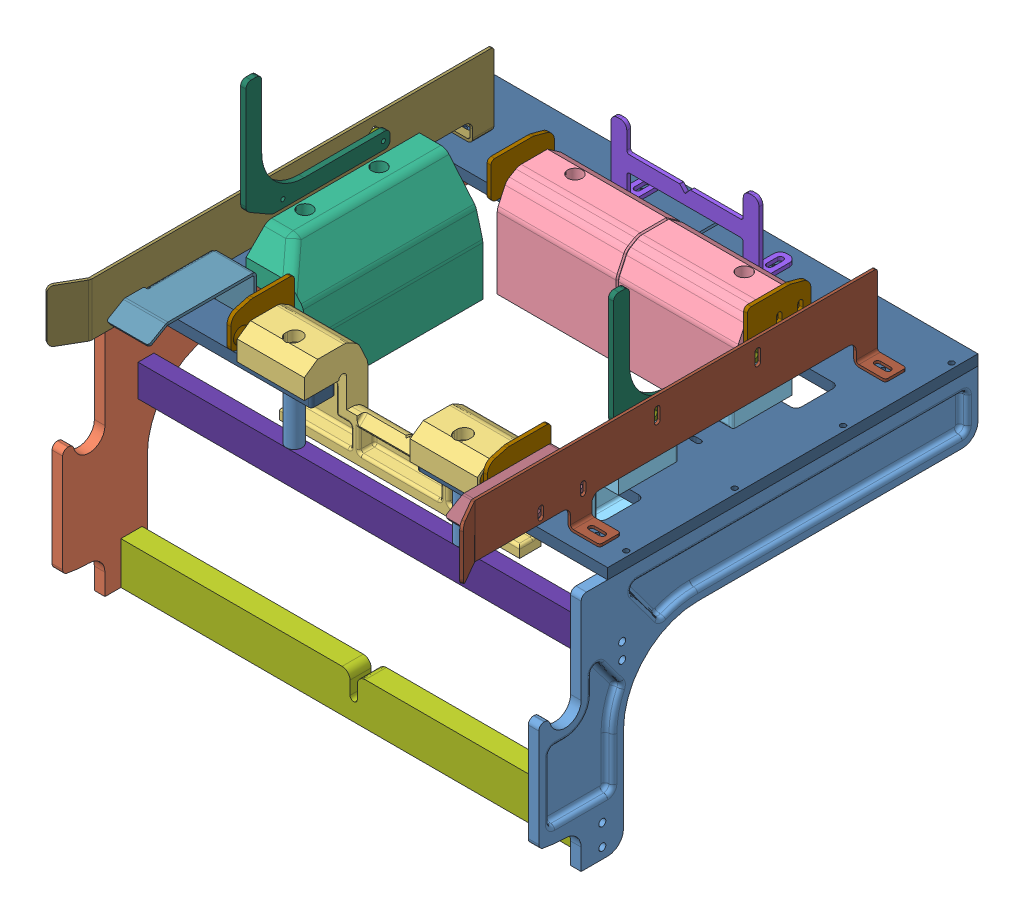
SolidWorks assembly FORMER PLATE ASSEMBLY, configuration Default. Lengths in mm.
Overall size (584.2 511.18 624.29).
42 component instances, 23 part files, 112 mates.
Components (placement in the parent):
- R&D5959 SHOW CARTON 5-30-18 LG-1: R&D5959 SHOW CARTON 5-30-18 LG [DEFAULT] at (0 -512.7625 36.5125) x (-1 0 0) z (0 0 -1) size (457.2 400.72 715.96) (hidden)
- MOUNT RIGHT-1: MOUNT RIGHT [Default] at (285.75 -156.3688 41.275) size (12.7 287.34 527.05)
- MOUNT LEFT-3: MOUNT LEFT [Default] at (-285.75 -156.3688 41.275) size (12.7 287.34 527.05)
- FOLDING PLATE BOTTOM-2: FOLDING PLATE BOTTOM [Default] at (0 -25.4 192.5637) size (288.13 120.65 76.2)
- FOLDING PLATE TOP-2: FOLDING PLATE TOP [Default] at (0 -25.4 -119.5387) x (-1 0 0) z (0 0 -1) size (288.13 120.65 76.2)
- FOLDING PLATE RIGHT-1: FOLDING PLATE RIGHT [Default] at (185.42 -18.2563 36.5125) x (0 0 -1) z (1 0 0) size (207.96 134.94 76.2)
- FOLDING PLATE LEFT-1: FOLDING PLATE LEFT [Default] at (-185.42 -18.2563 36.5125) x (0 0 1) z (-1 0 0) size (207.96 134.94 76.2)
- SPREADER BOTTOM-1: SPREADER BOTTOM [Default] at (0 -274.6375 222.25) x (1 0 0) z (0 0 -1) size (558.8 50.8 25.4)
- STOP RAIL-1: STOP RAIL [Default] at (0 0 -162.7188) x (0 0 -1) z (1 0 0) size (44.45 88.9 177.8)
- MINOR PLATE-1: MINOR PLATE [Default] at (156.2398 26.9875 192.5637) x (0 0 1) z (-1 0 0) size (76.2 44.45 4.55)
- MINOR PLATE-2: MINOR PLATE [Default] at (151.6856 26.9875 -119.5387) x (0 0 -1) z (1 0 0) size (76.2 44.45 4.55)
- MINOR PLATE-3: MINOR PLATE [Default] at (-156.2398 26.9875 -119.5387) x (0 0 -1) z (1 0 0) size (76.2 44.45 4.55)
- MINOR PLATE-4: MINOR PLATE [Default] at (-151.6856 26.9875 192.5637) x (0 0 1) z (-1 0 0) size (76.2 44.45 4.55)
- MAIN PLATE-2: MAIN PLATE [Default] at (0 -6.35 0) x (0 1 0) z (1 0 0) size (15.37 537.85 584.2)
- GUIDE RAIL-1: GUIDE RAIL [Default] at (228.6 0 79.375) x (-1 0 0) z (0 0 -1) size (38.1 88.9 517.3)
- GUIDE RAIL MIRROR-1: GUIDE RAIL MIRROR [Default] at (-228.6 0 79.375) x (-1 0 0) z (0 0 -1) size (38.1 88.9 517.3)
- SIDE GUIDE RIGHT-1: SIDE GUIDE RIGHT [Default] at (228.6 49.2125 216.6937) x (-1 0 0) z (0 0 1) size (50.8 76.2 129.64)
- SIDE GUIDE LEFT-1: SIDE GUIDE LEFT [Default] at (-228.6 49.2125 216.6937) x (-1 0 0) z (0 0 1) size (50.8 76.2 129.64)
- TOP GUIDE-1: TOP GUIDE [Default] at (223.8375 68.2625 57.9438) x (0 0 1) z (-1 0 0) size (173.02 152.4 6.35)
- TOP GUIDE-2: TOP GUIDE [Default] at (-217.4875 68.2625 57.9438) x (0 0 1) z (-1 0 0) size (173.02 152.4 6.35)
- SPACER2-1: SPACER2 [Default] at (226.2188 68.2625 -18.2563) x (0 0 -1) z (-1 0 0) size (15.88 15.88 4.76)
- SPACER2-3: SPACER2 [Default] at (226.2188 68.2625 102.3938) x (0 0 -1) z (-1 0 0) size (15.88 15.88 4.76)
- SPACER2-4: SPACER2 [Default] at (-226.2188 68.2625 -18.2563) x (0 0.924225 0.381849) z (1 0 0) size (15.88 15.88 4.76)
- SPACER2-5: SPACER2 [Default] at (-226.2188 68.2625 102.3938) x (0 0.99513 -0.098573) z (1 0 0) size (15.88 15.88 4.76)
- SPREADER TOP-1: SPREADER TOP [Default] at (0 -95.25 204.7875) x (-1 0 0) z (0 0 -1) size (558.8 38.1 19.05)
- SPACER1-1: SPACER1 [Default] at (147.8756 17.4625 -119.5387) x (0 0 -1) z (1 0 0) size (19.05 19.05 7.62)
- SPACER1-2: SPACER1 [Default] at (147.8756 17.4625 -144.9387) x (0 -0.924225 -0.381849) z (-1 0 0) size (19.05 19.05 7.62)
- SPACER1-3: SPACER1 [Default] at (147.8756 17.4625 192.5637) x (0 -0.924225 -0.381849) z (-1 0 0) size (19.05 19.05 7.62)
- SPACER1-4: SPACER1 [Default] at (147.8756 17.4625 217.9638) x (0 -0.924225 -0.381849) z (-1 0 0) size (19.05 19.05 7.62)
- SPACER1-5: SPACER1 [Default] at (-147.8756 17.4625 192.5637) x (0 0 -1) z (1 0 0) size (19.05 19.05 7.62)
- SPACER1-6: SPACER1 [Default] at (-147.8756 17.4625 217.9638) x (0 0 -1) z (1 0 0) size (19.05 19.05 7.62)
- SPACER1-7: SPACER1 [Default] at (-147.8756 17.4625 -119.5387) x (0 0 -1) z (1 0 0) size (19.05 19.05 7.62)
- SPACER1-8: SPACER1 [Default] at (-147.8756 17.4625 -144.9387) x (0 0 -1) z (1 0 0) size (19.05 19.05 7.62)
- BOLT MOUNT-1: BOLT MOUNT [Default] at (-101.6 -44.45 204.7875) x (1 0 0) z (0 -1 0) size (19.05 19.05 63.5)
- BOLT MOUNT-2: BOLT MOUNT [Default] at (101.6 -44.45 204.7875) x (0.877142 0 -0.48023) z (0 1 0) size (19.05 19.05 63.5)
- NUTPLATE LEFT AND RIGHT-1: NUTPLATE LEFT AND RIGHT [Default] at (212.4075 -15.875 36.5125) x (0 1 0) z (0 0 1) size (6.35 19.05 114.3)
- NUTPLATE LEFT AND RIGHT-2: NUTPLATE LEFT AND RIGHT [Default] at (-212.4075 -15.875 36.5125) x (0 -1 0) z (0 0 1) size (6.35 19.05 114.3)
- NUTPLATE TOP-1: NUTPLATE TOP [Default] at (0 -15.875 -132.2387) x (0 1 0) z (-1 0 0) size (6.35 19.05 228.6)
- NUTPLATE1-1: NUTPLATE1 [Default] at (123.4916 12.7 205.2637) x (0 0 -1) z (1 0 0) size (41.27 25.4 4.76)
- NUTPLATE1-2: NUTPLATE1 [Default] at (-128.2541 12.7 205.2637) x (0 0 -1) z (1 0 0) size (41.27 25.4 4.76)
- NUTPLATE1-3: NUTPLATE1 [Default] at (-128.3176 12.7 -132.2387) x (0 0 -1) z (1 0 0) size (41.27 25.4 4.76)
- NUTPLATE1-4: NUTPLATE1 [Default] at (128.3176 12.7 -132.2387) x (0 0 1) z (-1 0 0) size (41.27 25.4 4.76)
Mates (geometry in assembly coordinates):
- Coincident171: coincident: plane of MOUNT RIGHT-1 through (279.4 -12.7 304.8) normal (0 1 0); plane of MAIN PLATE-2 through (736.7814 -12.7 222.25) normal (0 -1 0)
- Coincident172: coincident: plane of MAIN PLATE-2 through (0 -6.35 0) normal (1 0 0); plane of assembly through (0 0 0) normal (1 0 0)
- Coincident173: coincident: plane of MAIN PLATE-2 through (0 -6.35 0) normal (0 0 1); plane of assembly through (0 0 0) normal (0 0 1)
- Coincident174: coincident: plane of MAIN PLATE-2 through (736.7814 0 222.25) normal (0 1 0); plane of assembly through (0 0 0) normal (0 1 0)
- Coincident175: coincident: plane of MAIN PLATE-2 through (736.7814 0 222.25) normal (0 1 0); plane of FOLDING PLATE BOTTOM-2 through (-144.0666 0 230.6637) normal (0 -1 0)
- Coincident176: coincident: plane of FOLDING PLATE TOP-2 through (0 -25.4 -119.5387) normal (-1 0 0); plane of assembly through (0 0 0) normal (1 0 0)
- Coincident177: coincident: plane of MAIN PLATE-2 through (736.7814 0 222.25) normal (0 1 0); plane of FOLDING PLATE TOP-2 through (144.0666 0 -157.6387) normal (0 -1 0)
- Coincident179: coincident: plane of R&D5959 SHOW CARTON 5-30-18 LG-1 through (0 -512.7625 36.5125) normal (-1 0 0); plane of assembly through (0 0 0) normal (1 0 0)
- Coincident182: coincident: plane of MAIN PLATE-2 through (736.7814 0 222.25) normal (0 1 0); plane of FOLDING PLATE RIGHT-1 through (223.52 0 140.4948) normal (0 -1 0)
- Coincident186: coincident: plane of FOLDING PLATE RIGHT-1 through (223.52 49.2125 140.4938) normal (0 1 0); plane of FOLDING PLATE LEFT-1 through (-223.52 49.2125 -67.4688) normal (0 1 0)
- Coincident191: coincident: plane of STOP RAIL-1 through (0 0 -162.7188) normal (1 0 0); plane of assembly through (0 0 0) normal (1 0 0)
- Coincident192: coincident: plane of MAIN PLATE-2 through (736.7814 0 222.25) normal (0 1 0); plane of STOP RAIL-1 through (88.9 0 -162.7188) normal (0 -1 0)
- Coincident196: coincident: plane of SPREADER BOTTOM-1 through (0 -274.6375 222.25) normal (1 0 0); plane of assembly through (0 0 0) normal (1 0 0)
- Coincident197: coincident: plane of FOLDING PLATE TOP-2 through (144.0656 34.925 -157.6387) normal (1 0 0); plane of SPACER1-1 through (144.0656 17.4625 -119.5387) normal (-1 0 0)
- Coincident1981: coincident: plane of FOLDING PLATE TOP-2 through (144.0656 34.925 -157.6387) normal (1 0 0); plane of SPACER1-2 through (144.0656 17.4625 -144.9387) normal (-1 0 0)
- Concentric591: concentric: cylinder of FOLDING PLATE BOTTOM-2 through (144.0656 17.4625 192.5637) axis (1 0 0) radius 3.2; cylinder of SPACER1-3 through (151.6866 17.4625 192.5637) axis (-1 0 0) radius 3.3782
- Coincident1991: coincident: plane of FOLDING PLATE BOTTOM-2 through (144.0656 34.925 230.6637) normal (1 0 0); plane of SPACER1-3 through (144.0656 17.4625 192.5637) normal (-1 0 0)
- Concentric601: concentric: cylinder of FOLDING PLATE BOTTOM-2 through (144.0656 17.4625 217.9638) axis (1 0 0) radius 3.2; cylinder of SPACER1-4 through (151.6866 17.4625 217.9638) axis (-1 0 0) radius 3.3782
- Coincident2001: coincident: plane of FOLDING PLATE BOTTOM-2 through (144.0656 34.925 230.6637) normal (1 0 0); plane of SPACER1-4 through (144.0656 17.4625 217.9638) normal (-1 0 0)
- Concentric611: concentric: cylinder of FOLDING PLATE BOTTOM-2 through (-144.0656 17.4625 192.5637) axis (-1 0 0) radius 3.2; cylinder of SPACER1-5 through (-151.6866 17.4625 192.5637) axis (1 0 0) radius 3.3782
- Coincident2011: coincident: plane of FOLDING PLATE BOTTOM-2 through (-144.0656 34.925 230.6637) normal (-1 0 0); plane of SPACER1-5 through (-144.0656 17.4625 192.5637) normal (1 0 0)
- Concentric621: concentric: cylinder of FOLDING PLATE BOTTOM-2 through (-144.0656 17.4625 217.9638) axis (-1 0 0) radius 3.2; cylinder of SPACER1-6 through (-151.6866 17.4625 217.9638) axis (1 0 0) radius 3.3782
- Coincident2021: coincident: plane of FOLDING PLATE BOTTOM-2 through (-144.0656 34.925 230.6637) normal (-1 0 0); plane of SPACER1-6 through (-144.0656 17.4625 217.9638) normal (1 0 0)
- Concentric631: concentric: cylinder of FOLDING PLATE TOP-2 through (-144.0656 17.4625 -119.5387) axis (-1 0 0) radius 3.2; cylinder of SPACER1-7 through (-151.6866 17.4625 -119.5387) axis (1 0 0) radius 3.3782
- Coincident2031: coincident: plane of FOLDING PLATE TOP-2 through (-144.0656 34.925 -157.6387) normal (-1 0 0); plane of SPACER1-7 through (-144.0656 17.4625 -119.5387) normal (1 0 0)
- Concentric641: concentric: cylinder of FOLDING PLATE TOP-2 through (-144.0656 17.4625 -144.9387) axis (-1 0 0) radius 3.2; cylinder of SPACER1-8 through (-151.6866 17.4625 -144.9387) axis (1 0 0) radius 3.3782
- Coincident2041: coincident: plane of FOLDING PLATE TOP-2 through (-144.0656 34.925 -157.6387) normal (-1 0 0); plane of SPACER1-8 through (-144.0656 17.4625 -144.9387) normal (1 0 0)
- Coincident205: coincident: plane of MINOR PLATE-1 through (151.6856 4.7625 154.4638) normal (-1 0 0); plane of SPACER1-4 through (151.6856 17.4625 217.9638) normal (1 0 0)
- Concentric65: concentric: cylinder of MINOR PLATE-1 through (156.2398 17.4625 217.9638) axis (-1 0 0) radius 3.175; cylinder of SPACER1-4 through (151.6866 17.4625 217.9638) axis (-1 0 0) radius 3.3782
- Concentric66: concentric: cylinder of MINOR PLATE-1 through (156.2398 17.4625 192.5637) axis (-1 0 0) radius 3.175; circle of SPACER1-3
- Coincident206: coincident: plane of SPACER1-1 through (151.6856 17.4625 -119.5387) normal (1 0 0); plane of MINOR PLATE-2 through (151.6856 4.7625 -81.4387) normal (-1 0 0)
- Concentric67: concentric: circle of SPACER1-1; cylinder of MINOR PLATE-2 through (151.6856 17.4625 -119.5387) axis (1 0 0) radius 3.175
- Concentric68: concentric: cylinder of SPACER1-2 through (151.6866 17.4625 -144.9387) axis (-1 0 0) radius 3.3782; cylinder of MINOR PLATE-2 through (151.6856 17.4625 -144.9387) axis (1 0 0) radius 3.175
- Coincident207: coincident: plane of SPACER1-7 through (-151.6856 17.4625 -119.5387) normal (-1 0 0); plane of MINOR PLATE-3 through (-151.6856 4.7625 -81.4387) normal (1 0 0)
- Concentric69: concentric: cylinder of SPACER1-7 through (-151.6866 17.4625 -119.5387) axis (1 0 0) radius 3.3782; cylinder of MINOR PLATE-3 through (-156.2398 17.4625 -119.5387) axis (1 0 0) radius 3.175
- Concentric70: concentric: cylinder of SPACER1-8 through (-144.0656 17.4625 -144.9387) axis (-1 0 0) radius 9.525; cylinder of MINOR PLATE-3 through (-156.2398 17.4625 -144.9387) axis (1 0 0) radius 3.175
- Coincident208: coincident: plane of SPACER1-6 through (-151.6856 17.4625 217.9638) normal (-1 0 0); plane of MINOR PLATE-4 through (-151.6856 4.7625 154.4638) normal (1 0 0)
- Concentric71: concentric: circle of SPACER1-5; cylinder of MINOR PLATE-4 through (-151.6856 17.4625 192.5637) axis (-1 0 0) radius 3.175
- Concentric72: concentric: cylinder of SPACER1-6 through (-151.6866 17.4625 217.9638) axis (1 0 0) radius 3.3782; cylinder of MINOR PLATE-4 through (-151.6856 17.4625 217.9638) axis (-1 0 0) radius 3.175
- Coincident2047: coincident: plane of MOUNT RIGHT-1 through (292.1 -300.0375 -222.25) normal (0 0 -1); plane of MAIN PLATE-2 through (736.7814 -12.7 -222.25) normal (0 0 -1)
- Coincident2048: coincident: plane of MOUNT RIGHT-1 through (292.1 -12.7 304.8) normal (1 0 0); plane of MAIN PLATE-2 through (292.1 -6.35 0) normal (1 0 0)
- Coincident2049: coincident: plane of MAIN PLATE-2 through (736.7814 -12.7 222.25) normal (0 -1 0); plane of MOUNT LEFT-3 through (-292.1 -12.7 304.8) normal (0 1 0)
- Coincident2050: coincident: plane of MAIN PLATE-2 through (736.7814 -12.7 -222.25) normal (0 0 -1); plane of MOUNT LEFT-3 through (-279.4 -300.0375 -222.25) normal (0 0 -1)
- Coincident2051: coincident: plane of MAIN PLATE-2 through (-292.1 -6.35 55.6563) normal (-1 0 0); plane of MOUNT LEFT-3 through (-292.1 -12.7 304.8) normal (-1 0 0)
- Distance13: distance = 19.05 mm: plane of SPREADER BOTTOM-1 through (279.4 -249.2375 234.95) normal (0 0 1); plane of MOUNT LEFT-3 through (-292.101 -12.7 254) normal (0 0 1)
- Coincident2053: coincident: plane of SPREADER BOTTOM-1 through (-279.4 -300.0375 209.55) normal (0 -1 0); plane of MOUNT LEFT-3 through (-292.1 -300.0375 304.8) normal (0 -1 0)
- Coincident2055: coincident: plane of MAIN PLATE-2 through (736.7814 0 222.25) normal (0 1 0); plane of GUIDE RAIL-1 through (228.6 0 -161.925) normal (0 -1 0)
- Coincident2056: coincident: plane of GUIDE RAIL-1 through (228.6 88.9 -161.925) normal (-1 0 0); plane of SIDE GUIDE RIGHT-1 through (228.6 30.1625 254.7937) normal (1 0 0)
- Coincident2059: coincident: plane of FOLDING PLATE RIGHT-1 through (223.52 49.2125 140.4938) normal (0 1 0); plane of SIDE GUIDE RIGHT-1 through (228.6 49.2125 254.7937) normal (0 1 0)
- Coincident2060: coincident: plane of MAIN PLATE-2 through (241.3 -12.701 178.5938) normal (0 0 -1); plane of SIDE GUIDE RIGHT-1 through (223.8375 44.45 178.5938) normal (0 0 -1)
- Coincident2062: coincident: plane of MAIN PLATE-2 through (736.7814 0 222.25) normal (0 1 0); plane of GUIDE RAIL MIRROR-1 through (-228.6 0 -161.925) normal (0 -1 0)
- Coincident2063: coincident: plane of GUIDE RAIL-1 through (234.95 6.35 -161.925) normal (0 0 -1); plane of GUIDE RAIL MIRROR-1 through (-234.95 6.35 -161.925) normal (0 0 -1)
- Coincident2065: coincident: plane of SIDE GUIDE RIGHT-1 through (228.6 46.0375 254.7937) normal (0 -1 0); plane of SIDE GUIDE LEFT-1 through (-228.6 46.0375 254.7937) normal (0 -1 0)
- Coincident2066: coincident: plane of GUIDE RAIL MIRROR-1 through (-228.6 88.9 -161.925) normal (1 0 0); plane of SIDE GUIDE LEFT-1 through (-228.6 30.1625 254.7937) normal (-1 0 0)
- Coincident2067: coincident: plane of SIDE GUIDE RIGHT-1 through (228.6 49.2125 173.8312) normal (0 0 -1); plane of SIDE GUIDE LEFT-1 through (-228.6 49.2125 173.8312) normal (0 0 -1)
- Parallel1: parallel: plane of MAIN PLATE-2 through (736.7814 0 222.25) normal (0 1 0); plane of STOP RAIL-1 through (88.9 4.5542 -162.7188) normal (0 1 0)
- Distance4: distance = 1.27 mm: plane of FOLDING PLATE TOP-2 through (-144.0656 -85.725 -81.4387) normal (0 0 1); line of MAIN PLATE-2 through (-146.05 -512.3053 -80.1688) axis (1 0 0)
- Distance5: distance = 1.27 mm: line of MAIN PLATE-2 through (-146.05 -512.3053 153.1937) axis (1 0 0); plane of FOLDING PLATE BOTTOM-2 through (144.0656 -85.725 154.4638) normal (0 0 -1)
- Distance6: distance = 1.27 mm: plane of FOLDING PLATE LEFT-1 through (-147.32 -85.725 140.4938) normal (1 0 0); line of MAIN PLATE-2 through (-146.05 -512.3053 -80.1688) axis (0 0 1)
- Distance7: distance = 1.27 mm: plane of FOLDING PLATE RIGHT-1 through (147.32 -85.725 -67.4688) normal (-1 0 0); line of MAIN PLATE-2 through (146.05 -512.3053 -80.1688) axis (0 0 1)
- Coincident2077: coincident: line of MAIN PLATE-2 through (146.05 -512.3053 36.5125) axis (-1 0 0); plane of FOLDING PLATE LEFT-1 through (-185.42 -18.2563 36.5125) normal (0 0 1)
- Coincident2078: coincident: plane of FOLDING PLATE BOTTOM-2 through (0 -25.4 192.5637) normal (1 0 0); plane of assembly through (0 0 0) normal (1 0 0)
- Coincident2081: coincident: line of MAIN PLATE-2 through (146.05 -512.3053 36.5125) axis (-1 0 0); plane of FOLDING PLATE RIGHT-1 through (185.42 -18.2563 36.5125) normal (0 0 -1)
- Distance8: distance = 15.875 mm: plane of MAIN PLATE-2 through (736.7814 -12.7 222.25) normal (0 0 1); plane of GUIDE RAIL-1 through (266.7 25.4 206.375) normal (0 0 1)
- Coincident2091: coincident: plane of TOP GUIDE-1 through (223.8375 58.7375 -30.9563) normal (1 0 0); plane of SPACER2-1 through (223.8375 68.2625 -18.2563) normal (-1 0 0)
- Concentric642: concentric: cylinder of TOP GUIDE-1 through (217.4875 68.2625 -18.2563) axis (-1 0 0) radius 2.5; cylinder of SPACER2-1 through (223.8375 68.2625 -18.2563) axis (1 0 0) radius 7.9375
- Concentric6431: concentric: cylinder of TOP GUIDE-1 through (217.4875 68.2625 102.3938) axis (-1 0 0) radius 2.5; cylinder of SPACER2-3 through (228.601 68.2625 102.3938) axis (-1 0 0) radius 3.3782
- Coincident20921: coincident: plane of TOP GUIDE-1 through (223.8375 58.7375 -30.9563) normal (1 0 0); plane of SPACER2-3 through (223.8375 68.2625 102.3938) normal (-1 0 0)
- Coincident2093: coincident: plane of GUIDE RAIL-1 through (228.6 88.9 -161.925) normal (-1 0 0); plane of SPACER2-1 through (228.6 68.2625 -18.2563) normal (1 0 0)
- Distance11: distance = 6.35 mm: plane of FOLDING PLATE RIGHT-1 through (223.52 49.2125 140.4938) normal (0 0 1); plane of TOP GUIDE-1 through (217.4875 77.7875 146.8438) normal (0 0 1)
- Distance9: distance = 9.525 mm: plane of FOLDING PLATE RIGHT-1 through (223.52 49.2125 140.4938) normal (0 1 0); plane of TOP GUIDE-1 through (217.4875 58.7375 -30.9563) normal (0 -1 0)
- Coincident2097: coincident: plane of TOP GUIDE-2 through (-223.8375 58.7375 -30.9563) normal (-1 0 0); plane of SPACER2-4 through (-223.8375 68.2625 -18.2563) normal (1 0 0)
- Concentric644: concentric: cylinder of TOP GUIDE-2 through (-223.8375 68.2625 -18.2563) axis (-1 0 0) radius 2.5; cylinder of SPACER2-4 through (-228.601 68.2625 -18.2563) axis (1 0 0) radius 3.3782
- Concentric6451: concentric: cylinder of TOP GUIDE-2 through (-223.8375 68.2625 102.3938) axis (-1 0 0) radius 2.5; cylinder of SPACER2-5 through (-228.601 68.2625 102.3938) axis (1 0 0) radius 3.3782
- Coincident20981: coincident: plane of TOP GUIDE-2 through (-223.8375 58.7375 -30.9563) normal (-1 0 0); plane of SPACER2-5 through (-223.8375 68.2625 102.3938) normal (1 0 0)
- Coincident2099: coincident: plane of GUIDE RAIL MIRROR-1 through (-228.6 88.9 -161.925) normal (1 0 0); plane of SPACER2-5 through (-228.6 68.2625 102.3938) normal (-1 0 0)
- Distance12: distance = 6.35 mm: plane of FOLDING PLATE LEFT-1 through (-223.52 49.2125 140.4938) normal (0 0 1); plane of TOP GUIDE-2 through (-223.8375 77.7875 146.8438) normal (0 0 1)
- Distance10: distance = 9.525 mm: plane of FOLDING PLATE LEFT-1 through (-223.52 49.2125 -67.4688) normal (0 1 0); plane of TOP GUIDE-2 through (-223.8375 58.7375 -30.9563) normal (0 -1 0)
- Coincident2102: coincident: plane of MAIN PLATE-2 through (736.7814 -12.7 222.25) normal (0 -1 0); plane of NUTPLATE TOP-1 through (-114.3 -12.7 -141.7637) normal (0 1 0)
- Coincident2103: coincident: plane of NUTPLATE TOP-1 through (0 -15.875 -132.2387) normal (-1 0 0); plane of assembly through (0 0 0) normal (1 0 0)
- Concentric646: concentric: cylinder of FOLDING PLATE TOP-2 through (101.6 34.925 -132.2387) axis (0 1 0) radius 3.3; cylinder of NUTPLATE TOP-1 through (101.6 -12.7 -132.2387) axis (0 1 0) radius 2.5
- Coincident2104: coincident: plane of MAIN PLATE-2 through (736.7814 -12.7 222.25) normal (0 -1 0); plane of NUTPLATE LEFT AND RIGHT-1 through (202.8825 -12.7 93.6625) normal (0 1 0)
- Coincident2105: coincident: plane of MAIN PLATE-2 through (736.7814 -12.7 222.25) normal (0 -1 0); plane of NUTPLATE LEFT AND RIGHT-2 through (-202.8825 -12.7 93.6625) normal (0 1 0)
- Coincident20982: coincident: plane of SPREADER TOP-1 through (0 -95.25 204.7875) normal (-1 0 0); plane of assembly through (0 0 0) normal (1 0 0)
- Distance14: distance = 17.4625 mm: plane of SPREADER TOP-1 through (0 -95.25 204.7875) normal (0 0 -1); plane of MAIN PLATE-2 through (736.7814 -12.7 222.25) normal (0 0 1)
- Distance15: distance = 63.5 mm: plane of MAIN PLATE-2 through (736.7814 -12.7 222.25) normal (0 -1 0); plane of SPREADER TOP-1 through (279.4 -76.2 195.2625) normal (0 1 0)
- Coincident20986: coincident: plane of SPREADER TOP-1 through (279.4 -76.2 195.2625) normal (0 1 0); plane of BOLT MOUNT-1 through (-101.6 -76.2 204.7875) normal (0 -1 0)
- Coincident20987: coincident: plane of SPREADER TOP-1 through (279.4 -76.2 195.2625) normal (0 1 0); plane of BOLT MOUNT-2 through (101.6 -76.2 204.7875) normal (0 -1 0)
- Concentric6452: concentric: cylinder of SPREADER TOP-1 through (-101.6 -76.2 204.7875) axis (0 1 0) radius 2.5; cylinder of BOLT MOUNT-1 through (-101.6 -76.2 204.7875) axis (0 1 0) radius 9.525
- Concentric6453: concentric: cylinder of SPREADER TOP-1 through (101.6 -76.2 204.7875) axis (0 1 0) radius 2.5; cylinder of BOLT MOUNT-2 through (101.6 -12.7 204.7875) axis (0 -1 0) radius 9.525
- Concentric6454: concentric: cylinder of FOLDING PLATE TOP-2 through (144.0656 17.4625 -144.9387) axis (1 0 0) radius 3.2; cylinder of SPACER1-2 through (144.0656 17.4625 -144.9387) axis (1 0 0) radius 9.525
- Parallel2: parallel: plane of FOLDING PLATE TOP-2 through (144.0656 34.925 -157.6387) normal (0 1 0); plane of MINOR PLATE-2 through (156.2398 49.2125 -157.6387) normal (0 1 0)
- Distance16: distance = 512.7625 mm: plane of R&D5959 SHOW CARTON 5-30-18 LG-1 through (-145.2562 -512.7625 234.1562) normal (0 -1 0); plane of MAIN PLATE-2 through (736.7814 0 222.25) normal (0 1 0)
- Concentric6455: concentric: cylinder of FOLDING PLATE BOTTOM-2 through (144.0656 17.4625 192.5637) axis (1 0 0) radius 3.2; cylinder of NUTPLATE1-1 through (128.2541 17.4625 192.5637) axis (1 0 0) radius 2.5
- Concentric6456: concentric: cylinder of FOLDING PLATE BOTTOM-2 through (144.0656 17.4625 217.9638) axis (1 0 0) radius 3.2; cylinder of NUTPLATE1-1 through (128.2541 17.4625 217.9638) axis (1 0 0) radius 2.5
- Coincident20988: coincident: plane of FOLDING PLATE BOTTOM-2 through (128.2541 25.654 226.2981) normal (-1 0 0); plane of NUTPLATE1-1 through (128.2541 0 225.9013) normal (1 0 0)
- Concentric6457: concentric: cylinder of FOLDING PLATE BOTTOM-2 through (-144.0656 17.4625 192.5637) axis (-1 0 0) radius 3.2; cylinder of NUTPLATE1-2 through (-123.4916 17.4625 192.5637) axis (1 0 0) radius 2.5
- Concentric6458: concentric: cylinder of FOLDING PLATE BOTTOM-2 through (-144.0656 17.4625 217.9638) axis (-1 0 0) radius 3.2; cylinder of NUTPLATE1-2 through (-123.4916 17.4625 217.9638) axis (1 0 0) radius 2.5
- Coincident20989: coincident: plane of FOLDING PLATE BOTTOM-2 through (-128.2541 25.654 226.2981) normal (1 0 0); plane of NUTPLATE1-2 through (-128.2541 0 225.9013) normal (-1 0 0)
- Coincident20990: coincident: plane of FOLDING PLATE TOP-2 through (128.3176 25.4 -153.2731) normal (-1 0 0); plane of NUTPLATE1-4 through (128.3176 0 -152.8762) normal (1 0 0)
- Concentric6459: concentric: cylinder of FOLDING PLATE TOP-2 through (144.0656 17.4625 -119.5387) axis (1 0 0) radius 3.2; cylinder of NUTPLATE1-4 through (123.5551 17.4625 -119.5387) axis (-1 0 0) radius 2.5
- Concentric6460: concentric: cylinder of FOLDING PLATE TOP-2 through (144.0656 17.4625 -144.9387) axis (1 0 0) radius 3.2; cylinder of NUTPLATE1-4 through (123.5551 17.4625 -144.9387) axis (-1 0 0) radius 2.5
- Coincident20991: coincident: plane of FOLDING PLATE TOP-2 through (-128.3176 25.4 -153.2731) normal (1 0 0); plane of NUTPLATE1-3 through (-128.3176 0 -111.6012) normal (-1 0 0)
- Concentric6461: concentric: cylinder of FOLDING PLATE TOP-2 through (-144.0656 17.4625 -119.5387) axis (-1 0 0) radius 3.2; cylinder of NUTPLATE1-3 through (-123.5551 17.4625 -119.5387) axis (1 0 0) radius 2.5
- Concentric6462: concentric: cylinder of FOLDING PLATE TOP-2 through (-144.0656 17.4625 -144.9387) axis (-1 0 0) radius 3.2; cylinder of NUTPLATE1-3 through (-123.5551 17.4625 -144.9387) axis (1 0 0) radius 2.5
- Distance21: distance = 5.08 mm: plane of FOLDING PLATE RIGHT-1 through (223.52 -85.725 -67.4688) normal (1 0 0); plane of GUIDE RAIL-1 through (228.6 88.9 -161.925) normal (-1 0 0)
- Distance22: distance = 5.08 mm: plane of GUIDE RAIL MIRROR-1 through (-228.6 88.9 -161.925) normal (1 0 0); plane of FOLDING PLATE LEFT-1 through (-223.52 -85.725 140.4938) normal (-1 0 0)
- Distance23: distance = 5.08 mm: plane of STOP RAIL-1 through (88.9 88.9 -162.7188) normal (0 0 1); plane of FOLDING PLATE TOP-2 through (-144.0656 -85.725 -157.6387) normal (0 0 -1)
- Distance24: distance = 0.3175 mm: plane of MAIN PLATE-2 through (-203.2 -12.701 127.7938) normal (1 0 0); plane of NUTPLATE LEFT AND RIGHT-2 through (-202.8825 -12.7 93.6625) normal (1 0 0)
- Slot1: slot: cylinder of NUTPLATE LEFT AND RIGHT-2 through (-212.4075 -19.05 36.5125) axis (0 -1 0) radius 2.5; cylinder of MAIN PLATE-2 through (-215.5825 0 36.5125) axis (0 -1 0) radius 3.175; cylinder of MAIN PLATE-2 through (-209.2325 0 36.5125) axis (0 -1 0) radius 3.175
- Distance25: distance = 0.3175 mm: plane of NUTPLATE LEFT AND RIGHT-1 through (202.8825 -19.05 93.6625) normal (-1 0 0); plane of MAIN PLATE-2 through (203.2 -12.701 127.7938) normal (-1 0 0); cylinder of MAIN PLATE-2; cylinder of NUTPLATE LEFT AND RIGHT-1; cylinder of MAIN PLATE-2
- Slot2: slot: cylinder of MAIN PLATE-2 through (209.2325 0 36.5125) axis (0 -1 0) radius 3.175; cylinder of NUTPLATE LEFT AND RIGHT-1 through (212.4075 -12.7 36.5125) axis (0 1 0) radius 2.5; cylinder of MAIN PLATE-2 through (215.5825 0 36.5125) axis (0 -1 0) radius 3.175
